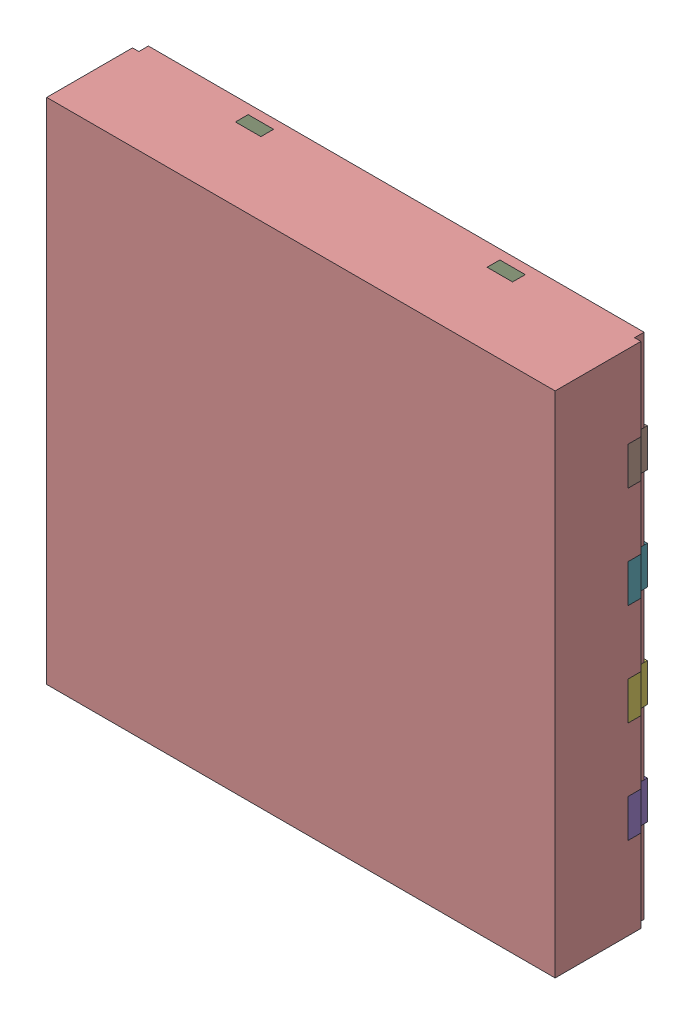
SolidWorks assembly NGU0008C_ASM, configuration По умолчанию. Lengths in mm.
Overall size (4 4 0.78).
11 component instances, 10 part files, 0 mates.
Components (placement in the parent):
- FRAME-NGU0008C_AF0-1: FRAME-NGU0008C_AF0 [По умолчанию] x (1 0 0) z (0 -1 0) size (4 0.2 4)
  - FRAME-NGU0008C_AF0-Part-1-1: FRAME-NGU0008C_AF0-Part-1 [По умолчанию] at origin size (0.4 0.2 0.3)
  - FRAME-NGU0008C_AF0-Part-2-1: FRAME-NGU0008C_AF0-Part-2 [По умолчанию] at origin size (0.4 0.2 0.3)
  - FRAME-NGU0008C_AF0-Part-3-1: FRAME-NGU0008C_AF0-Part-3 [По умолчанию] at origin size (0.4 0.2 0.3)
  - FRAME-NGU0008C_AF0-Part-4-1: FRAME-NGU0008C_AF0-Part-4 [По умолчанию] at origin size (0.4 0.2 0.3)
  - FRAME-NGU0008C_AF0-Part-5-1: FRAME-NGU0008C_AF0-Part-5 [По умолчанию] at origin size (0.4 0.2 0.3)
  - FRAME-NGU0008C_AF0-Part-6-1: FRAME-NGU0008C_AF0-Part-6 [По умолчанию] at origin size (0.4 0.2 0.3)
  - FRAME-NGU0008C_AF0-Part-7-1: FRAME-NGU0008C_AF0-Part-7 [По умолчанию] at origin size (0.4 0.2 0.3)
  - FRAME-NGU0008C_AF0-Part-8-1: FRAME-NGU0008C_AF0-Part-8 [По умолчанию] at origin size (0.4 0.2 0.3)
  - FRAME-NGU0008C_AF0-Part-9-1: FRAME-NGU0008C_AF0-Part-9 [По умолчанию] at origin size (2.18 0.2 4)
- NGU0008C_ASM-Part-1-1: NGU0008C_ASM-Part-1 [По умолчанию] at (0 0 0.025) x (1 0 0) z (0 -1 0) size (4 0.75 4)
